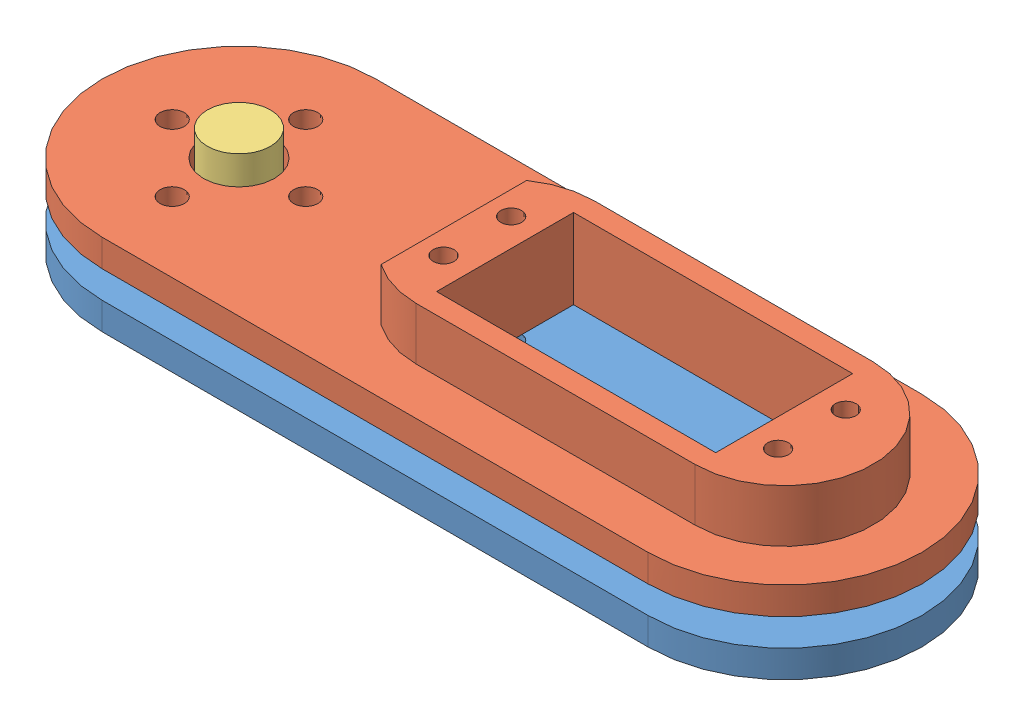
SolidWorks assembly jambe, configuration Défaut. Lengths in mm.
Overall size (120.14 21.66 40.13).
3 component instances, 3 part files, 8 mates.
Components (placement in the parent):
- New_thigh_2-1: New_thigh_2 [Default] at (-33.0127 -12.4775 120.142) size (120.14 4 40.13)
- New_thigh-1: New_thigh [Default] at (-33.0127 -4.475 120.142) size (120.14 11.7 40.13)
- New_adapter-1: New_adapter [Default] at (-33.0127 -8.475 120.142) size (31.75 17.76 31.75)
Mates (geometry in assembly coordinates):
- Coaxiale1: concentric aligned: cylinder of New_thigh_2-1 through (-33.0127 -13.0175 120.142) axis (0 1 0) radius 20.066; cylinder of New_thigh-1 through (-33.0127 -5.015 120.142) axis (0 1 0) radius 20.066
- Coaxiale2: concentric aligned: cylinder of New_thigh_2-1 through (46.9973 -13.0175 120.142) axis (0 1 0) radius 20.066; cylinder of New_thigh-1 through (46.9973 -5.015 120.142) axis (0 1 0) radius 20.066
- Coïncidente1: coincident anti-aligned: plane of New_thigh-1 through (46.9973 6.6875 120.269) normal (0 1 0); plane of moteur-1 through (15.6487 12.0385 110.49) normal (0 -1 0)
- Coïncidente2: coincident anti-aligned: plane of New_thigh-1 through (6.1033 -0.2515 130.302) normal (1 0 0); plane of moteur-1 through (6.1033 20.5221 130.302) normal (-1 0 0)
- Coïncidente3: coincident anti-aligned: plane of New_thigh-1 through (46.9973 -0.2515 130.302) normal (0 0 -1); plane of moteur-1 through (26.0423 20.5221 130.302) normal (0 0 1)
- Coaxiale3: concentric anti-aligned: cylinder of New_thigh_2-1 through (-33.0127 -9.015 120.142) axis (0 -1 0) radius 5.2; cylinder of New_adapter-1 through (-33.0127 -14.975 120.142) axis (0 1 0) radius 4.627
- Coïncidente4: coincident anti-aligned: plane of New_thigh_2-1 through (-33.0127 -9.015 120.142) normal (0 1 0); plane of New_adapter-1 through (-33.0127 -9.015 120.142) normal (0 -1 0)
- Coïncidente5: coincident anti-aligned: plane of New_thigh-1 through (-33.0127 -5.015 120.142) normal (0 -1 0); plane of New_adapter-1 through (-33.0127 -5.015 120.142) normal (0 1 0)
